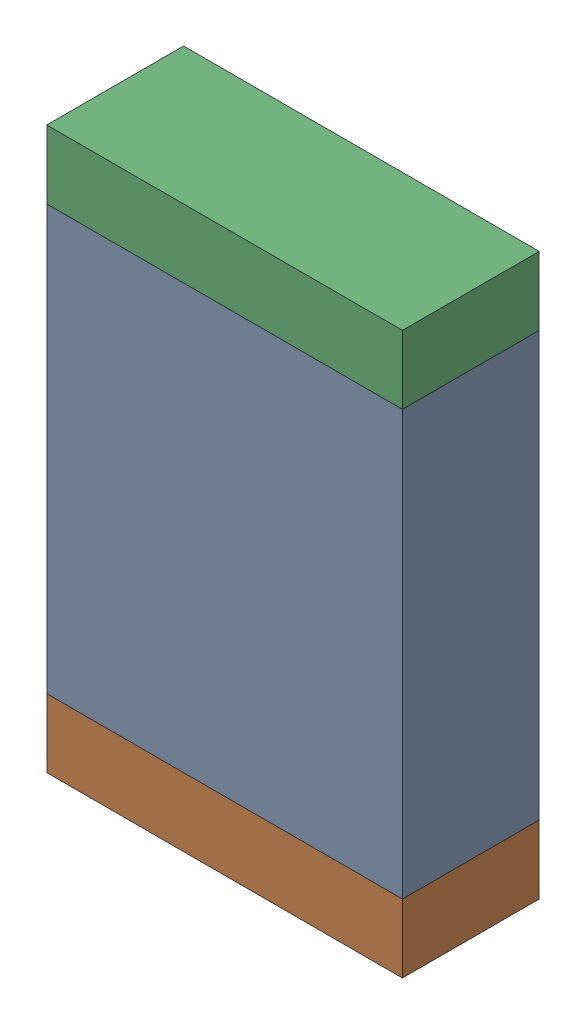
SolidWorks assembly C102, configuration Default. Lengths in mm.
Overall size (1.3 2.05 0.5).
6 component instances, 2 part files, 0 mates.
Components (placement in the parent):
- 836753008-1: 836753008 [Default] at (108.45 71.725 0) size (1.3 1.55 0.5)
  - Extruded_23-1: Extruded_23 [Default] at origin size (1.3 1.55 0.5)
- 836753264-1: 836753264 [Default] at (108.45 70.825 0) size (1.3 0.25 0.5)
  - Extruded_22-1: Extruded_22 [Default] at origin size (1.3 0.25 0.5)
- 836753264-2: 836753264 [Default] at (108.45 72.625 0) size (1.3 0.25 0.5)
  - Extruded_22-1: Extruded_22 [Default] at origin size (1.3 0.25 0.5)
